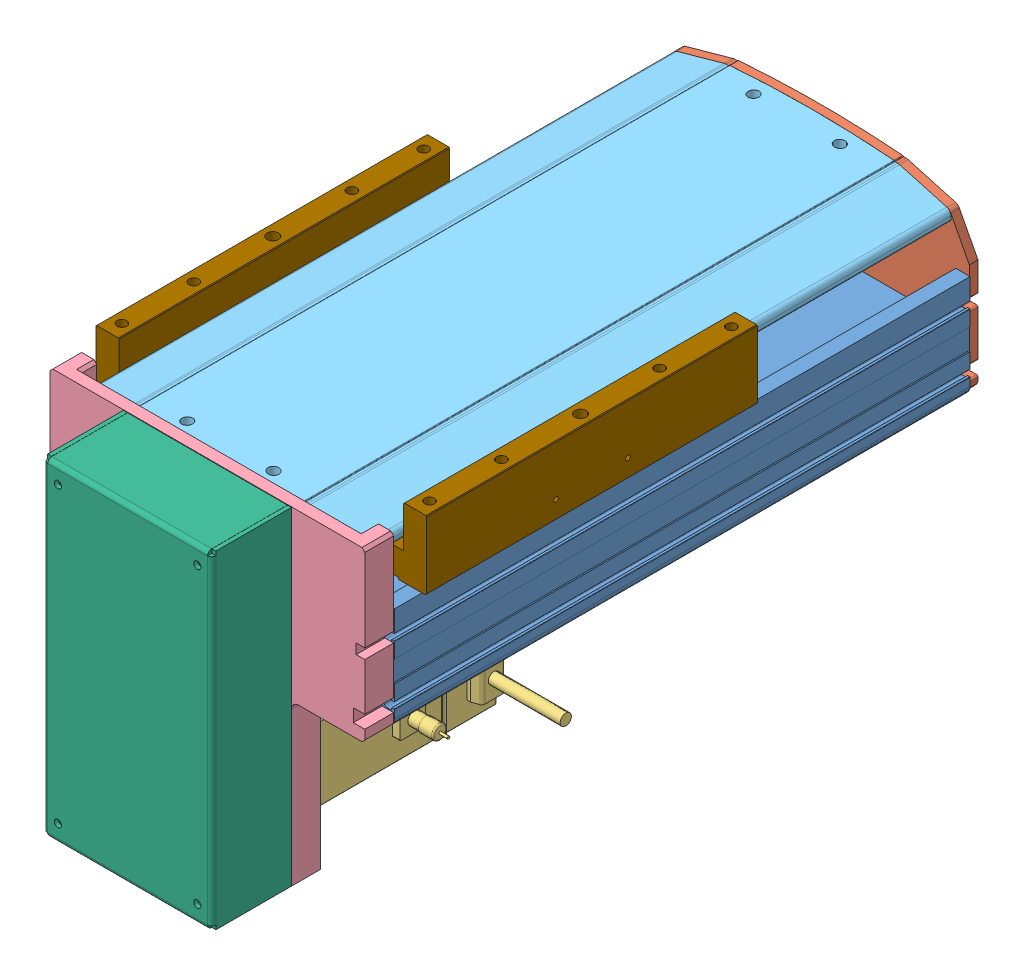
SolidWorks assembly S22-BM-750W, configuration 默认. Lengths in mm.
Overall size (238.5 232.51 482.01).
11 component instances, 9 part files, 36 mates.
Components (placement in the parent):
- S22-BL底座^S22-BM-750W-1: S22-BL底座^S22-BM-750W [默认] at origin size (220 72.2 400.5) (virtual)
- S22-GY侧盖^S22-BM-750W-1: S22-GY侧盖^S22-BM-750W [默认] at (0 0 -206.25) size (219 117 6) (virtual)
- 750W电机^S22-BM-750W-1: 750W电机^S22-BM-750W [默认] at (0 -65.31 58.25) x (0 1 0) z (0 0 1) size (82 139.7 182) (virtual)
- S22-BM-P75电机板^S22-BM-750W-1: S22-BM-P75电机板^S22-BM-750W [默认] at (0 0 200.25) size (219 228.5 20) (virtual)
- S22-BM上盖^S22-BM-750W-1: S22-BM上盖^S22-BM-750W [默认] at (0 117.9988 6) size (193.4 19.6 412.5) (virtual)
- S22-BM盖子^S22-BM-750W-1: S22-BM盖子^S22-BM-750W [默认] at (0 3.55 275.75) x (0 1 0) z (0 0 1) size (228.12 117 55.51) (virtual)
- EE-SX672 传感器^S22-BM-750W-1: EE-SX672 传感器^S22-BM-750W [默认] at (-116.75 61.1 -40.25) x (-1 0 0) z (0 0 1) size (13.5 27.4 26.1) (virtual)
- S22-GY外置感应片^S22-BM-750W-1: S22-GY外置感应片^S22-BM-750W [默认] at (-115.8 87 67.75) x (0 0 -1) z (1 0 0) size (70 27 0.8) (virtual)
- EE-SX672 传感器^S22-BM-750W-2: EE-SX672 传感器^S22-BM-750W [默认] at (-116.75 61.1 77.65) x (-1 0 0) z (0 0 1) size (13.5 27.4 26.1) (virtual)
- EE-SX672 传感器^S22-BM-750W-3: EE-SX672 传感器^S22-BM-750W [默认] at (-116.75 61.1 51.55) x (-1 0 0) z (0 0 1) size (13.5 27.4 26.1) (virtual)
- S22-BL-SFS25滑座^S22-BM-750W-1: S22-BL-SFS25滑座^S22-BM-750W [默认] at (0 0 67.75) size (230 80 230) (virtual)
Mates (geometry in assembly coordinates):
- 重合1: coincident: plane of S22-BL底座^S22-BM-750W-1 through (0 0 0) normal (1 0 0); plane of assembly through (0 0 0) normal (1 0 0)
- 重合2: coincident: plane of S22-BL底座^S22-BM-750W-1 through (0 0 0) normal (0 1 0); plane of assembly through (0 0 0) normal (0 1 0)
- 重合3: coincident: plane of S22-BL底座^S22-BM-750W-1 through (0 0 0) normal (0 0 1); plane of assembly through (0 0 0) normal (0 0 1)
- 重合5: coincident: plane of S22-BL底座^S22-BM-750W-1 through (0 0 0) normal (1 0 0); plane of S22-GY侧盖^S22-BM-750W-1 through (0 0 -206.25) normal (1 0 0)
- 重合6: coincident: plane of S22-BL底座^S22-BM-750W-1 through (0 0 0) normal (0 1 0); plane of S22-GY侧盖^S22-BM-750W-1 through (0 0 -206.25) normal (0 1 0)
- 重合28: coincident: plane of S22-BL底座^S22-BM-750W-1 through (0 0 0) normal (0 1 0); plane of S22-BM-P75电机板^S22-BM-750W-1 through (0 0 200.25) normal (0 1 0)
- 重合29: coincident: plane of S22-BL底座^S22-BM-750W-1 through (0 0 0) normal (1 0 0); plane of S22-BM-P75电机板^S22-BM-750W-1 through (0 0 200.25) normal (1 0 0)
- 重合30: coincident: plane of S22-BL底座^S22-BM-750W-1 through (-104.5 14 200.25) normal (0 0 1); plane of S22-BM-P75电机板^S22-BM-750W-1 through (0 0 200.25) normal (0 0 -1)
- 重合36: coincident: plane of S22-BL底座^S22-BM-750W-1 through (0 0 0) normal (1 0 0); plane of S22-BM上盖^S22-BM-750W-1 through (0 117.9988 6) normal (1 0 0)
- 平行6: parallel: plane of S22-BL底座^S22-BM-750W-1 through (110 16.25 200.25) normal (1 0 0); plane of 750W电机^S22-BM-750W-1 through (40 -25.31 58.25) normal (1 0 0)
- 重合146: coincident: plane of 750W电机^S22-BM-750W-1 through (0 -65.31 200.25) normal (0 0 1); plane of S22-BM-P75电机板^S22-BM-750W-1 through (0 0 200.25) normal (0 0 -1)
- 重合191: coincident: plane of S22-BM-P75电机板^S22-BM-750W-1 through (0 0 220.25) normal (0 0 1); plane of S22-BM盖子^S22-BM-750W-1 through (-58.5 114.8 220.25) normal (0 0 -1)
- 重合192: coincident: plane of S22-BL底座^S22-BM-750W-1 through (0 0 0) normal (1 0 0); plane of S22-BM盖子^S22-BM-750W-1 through (0 3.55 275.75) normal (-1 0 0)
- 重合193: coincident: plane of S22-BM-P75电机板^S22-BM-750W-1 through (-58.5 -110.5 381.8707) normal (0 -1 0); plane of S22-BM盖子^S22-BM-750W-1 through (-55.6 -110.5 272.95) normal (0 -1 0)
- 重合196: coincident: plane of S22-BL底座^S22-BM-750W-1 through (-104.5 14 -200.25) normal (0 0 -1); plane of S22-GY侧盖^S22-BM-750W-1 through (0 -619.785 -200.25) normal (0 0 1)
- 重合198: coincident: plane of S22-GY侧盖^S22-BM-750W-1 through (0 -619.785 -200.25) normal (0 0 1); plane of S22-BM上盖^S22-BM-750W-1 through (59.5897 110.29 -200.25) normal (0 0 -1)
- Coincident1: coincident: plane of 750W电机^S22-BM-750W-1 through (0 -65.31 58.25) normal (-1 0 0); plane of S22-BM-P75电机板^S22-BM-750W-1 through (0 0 200.25) normal (1 0 0)
- Distance1: distance = 6.5 mm: plane of 750W电机^S22-BM-750W-1 through (33 -105.31 192.25) normal (0 -1 0); plane of S22-BM盖子^S22-BM-750W-1 through (-55.6 -110.5 272.95) normal (0 -1 0)
- Distance2: distance = 122 mm: plane of S22-BL-SFS25滑座^S22-BM-750W-1 through (99 122 182.75) normal (0 1 0); plane of S22-BL底座^S22-BM-750W-1 through (110 0 200.25) normal (0 -1 0)
- Distance3: distance = 117.9988 mm: plane of S22-BM上盖^S22-BM-750W-1 through (0 117.9988 6) normal (0 1 0); plane of S22-BL底座^S22-BM-750W-1 through (0 0 0) normal (0 1 0)
- Coincident4: coincident: plane of S22-BL底座^S22-BM-750W-1 through (0 0 0) normal (1 0 0); plane of S22-BL-SFS25滑座^S22-BM-750W-1 through (0 0 67.75) normal (1 0 0)
- Coincident5: coincident: plane of EE-SX672 传感器^S22-BM-750W-1 through (-110 72.2 -33.95) normal (1 0 0); plane of EE-SX672 传感器^S22-BM-750W-2 through (-110 72.2 83.95) normal (1 0 0)
- Coincident6: coincident: plane of EE-SX672 传感器^S22-BM-750W-2 through (-110 72.2 83.95) normal (1 0 0); plane of EE-SX672 传感器^S22-BM-750W-3 through (-110 72.2 57.85) normal (1 0 0)
- Coincident7: coincident: plane of EE-SX672 传感器^S22-BM-750W-1 through (-110 50 -33.95) normal (0 -1 0); plane of EE-SX672 传感器^S22-BM-750W-2 through (-110 50 83.95) normal (0 -1 0)
- Coincident8: coincident: plane of EE-SX672 传感器^S22-BM-750W-2 through (-110 50 83.95) normal (0 -1 0); plane of EE-SX672 传感器^S22-BM-750W-3 through (-110 50 57.85) normal (0 -1 0)
- Coincident9: coincident: plane of EE-SX672 传感器^S22-BM-750W-2 through (-113 53.2 67.75) normal (0 0 -1); plane of EE-SX672 传感器^S22-BM-750W-3 through (-113 53.2 67.75) normal (0 0 1)
- Coincident10: coincident: plane of S22-BL底座^S22-BM-750W-1 through (-110 42 200.25) normal (-1 0 0); plane of EE-SX672 传感器^S22-BM-750W-2 through (-110 72.2 83.95) normal (1 0 0)
- Distance4: distance = 50 mm: plane of EE-SX672 传感器^S22-BM-750W-1 through (-110 50 -33.95) normal (0 -1 0); plane of S22-BL底座^S22-BM-750W-1 through (-110 0 200.25) normal (0 -1 0)
- Coincident12: coincident: plane of S22-BL-SFS25滑座^S22-BM-750W-1 through (-115 122 182.75) normal (-1 0 0); plane of S22-GY外置感应片^S22-BM-750W-1 through (-115 91 101.75) normal (1 0 0)
- Concentric1: concentric: cylinder of S22-BL-SFS25滑座^S22-BM-750W-1 through (-115 87 92.75) axis (-1 0 0) radius 1.65; cylinder of S22-GY外置感应片^S22-BM-750W-1 through (-115 87 92.75) axis (-1 0 0) radius 2.75
- Concentric2: concentric: cylinder of S22-BL-SFS25滑座^S22-BM-750W-1 through (-115 87 42.75) axis (-1 0 0) radius 1.65; cylinder of S22-GY外置感应片^S22-BM-750W-1 through (-115 87 42.75) axis (-1 0 0) radius 2.75
- 距离1: distance = 186 mm: plane of EE-SX672 传感器^S22-BM-750W-2 through (-123.5 50 83.95) normal (0 0 1); plane of S22-BM盖子^S22-BM-750W-1 through (-58.5 114.8 275.75) normal (0 0 1)
- 距离2: distance = 166 mm: plane of S22-GY侧盖^S22-BM-750W-1 through (0 -619.785 -206.25) normal (0 0 -1); plane of EE-SX672 传感器^S22-BM-750W-1 through (-123.5 50 -40.25) normal (0 0 -1)
- 宽度1: width: plane of EE-SX672 传感器^S22-BM-750W-3 through (-123.5 50 57.85) normal (0 0 1); plane of EE-SX672 传感器^S22-BM-750W-2 through (-123.5 50 77.65) normal (0 0 -1); plane of S22-GY外置感应片^S22-BM-750W-1 through (-115 65 73.75) normal (0 0 1); plane of S22-GY外置感应片^S22-BM-750W-1 through (-115 65 61.75) normal (0 0 -1)
- 距离3: distance = 65.31 mm: plane of S22-BL底座^S22-BM-750W-1 through (110 0 200.25) normal (0 -1 0); cylinder of 750W电机^S22-BM-750W-1 through (0 -65.31 203.25) axis (0 0 1) radius 9.5
- 距离4: distance = 208 mm: cylinder of S22-BL-SFS25滑座^S22-BM-750W-1 through (107 122 67.75) axis (0 1 0) radius 4; plane of S22-BM盖子^S22-BM-750W-1 through (-58.5 114.8 275.75) normal (0 0 1)
